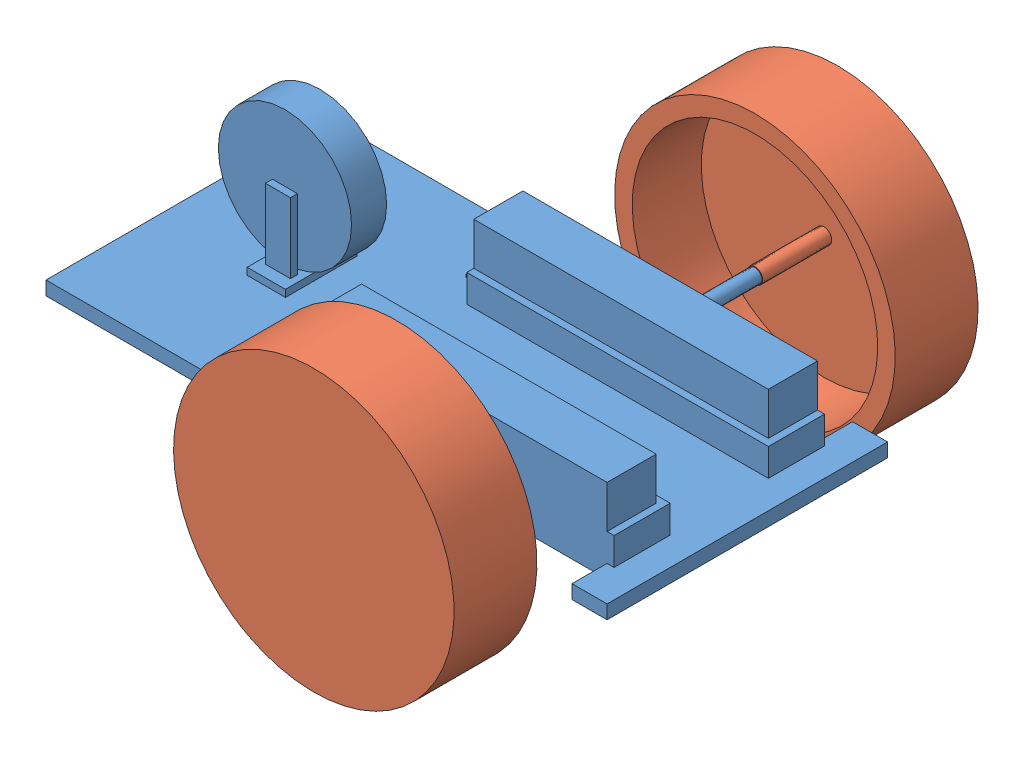
SolidWorks assembly Assem1, configuration Default. Lengths in mm.
Overall size (209.56 139.71 189.76).
3 component instances, 2 part files, 2 mates.
Components (placement in the parent):
- Part2-1: Part2 [Default] at (38.524 92.0146 167.7173) size (203.2 57.07 130.81)
- wheell-1: wheell [Default] at (76.624 109.7146 261.2173) x (-0.852635 0.522507 0) z (-0.522507 -0.852635 0) size (101.6 30 101.6)
- wheell-2: wheell [Default] at (76.624 109.7146 71.4569) x (1 0 0) z (0 -1 0) size (101.6 30 101.6)
Mates (geometry in assembly coordinates):
- Coincident1: coincident anti-aligned: circle of Part2-1; circle of wheell-1
- Concentric1: concentric anti-aligned: circle of Part2-1; circle of wheell-2
